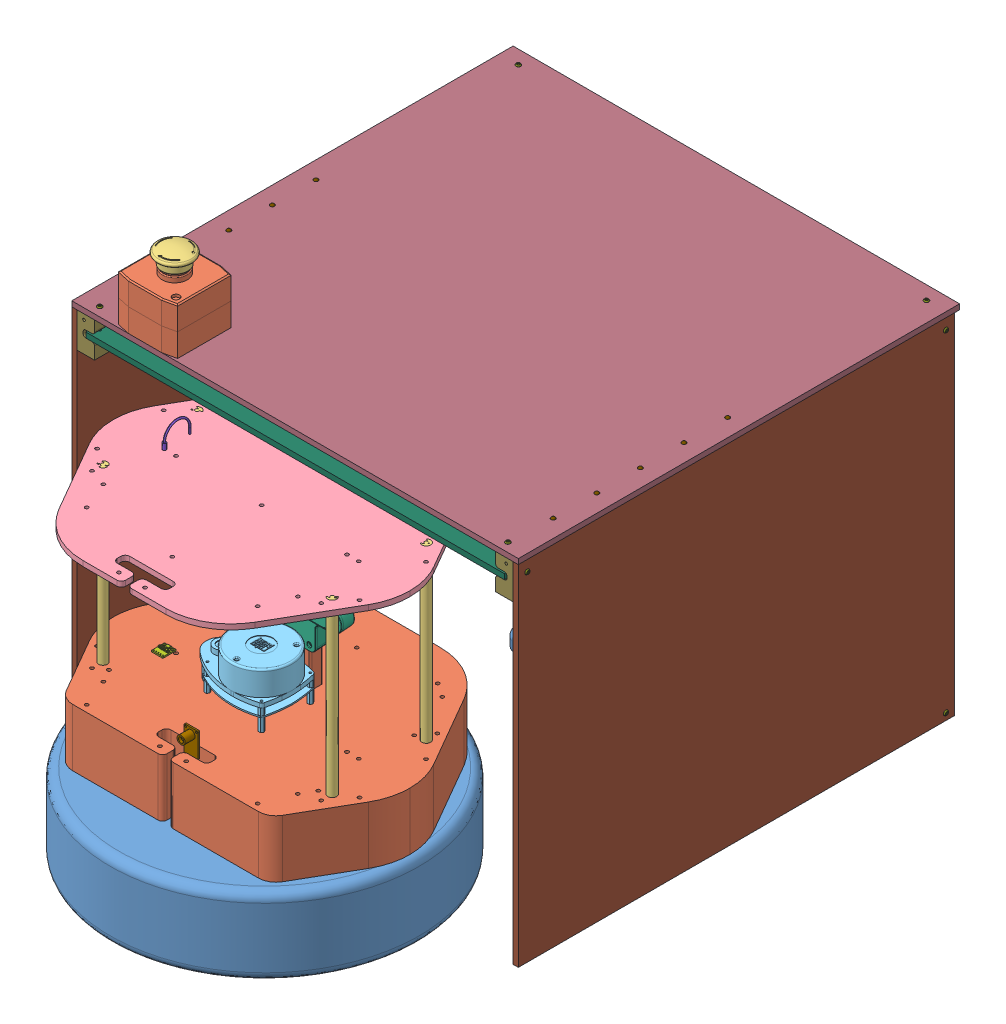
SolidWorks assembly robot_dock_with_robot, configuration Default. Lengths in mm.
Overall size (515 484.72 722.06).
59 component instances, 21 part files, 14 mates.
Components (placement in the parent):
- Turtlebot4Assem-1: Turtlebot4Assem [Default] at (298.995 1.0386 682.8626) x (-1 0 0) z (0 0 -1) size (354 373.83 354)
  - Kobuki Base-1: Kobuki Base [Default] at (151.4984 129.222 268.9926) size (354 89 354)
  - Layer A-1: Layer A [Default] at (151.4984 278.222 265.3926) size (340 111 267.27)
  - ROD-1: ROD [Default] at (282.8984 218.222 322.8926) x (-0.326124 0 0.945327) z (-0.945327 0 -0.326124) size (10 262 10)
  - ROD-2: ROD [Default] at (282.8984 218.222 215.0926) x (0.242222 0 0.970221) z (-0.970221 0 0.242222) size (10 262 10)
  - ROD-3: ROD [Default] at (20.0984 218.222 322.8926) x (0.560447 0 0.828191) z (-0.828191 0 0.560447) size (10 262 10)
  - ROD-4: ROD [Default] at (20.0984 218.222 215.0926) size (10 262 10)
  - Layer C-1: Layer C [Default] at (151.4984 474.222 265.3926) size (340 6 287.27)
  - rplidar_main-1: rplidar_main [По умолчанию] at (165.7484 308.822 265.3942) size (98.5 57.7 70.02)
  - OAK-D-parts-14sep2020.stp-3: OAK-D-parts-14sep2020.stp [Default] at (149.808 370.0152 305.3942) x (-1 0 0) z (0 0 -1) size (110 54.5 33.05)
  - OSNOVANIE.stp-1: OSNOVANIE.stp [Default] at (251.9304 284.222 252.7128) x (0.999998 0 -0.001829) z (0 1 0) size (13.1 15 3.05)
  - ds18b20.step-1: ds18b20.step [Default] at (262.9536 452.1028 265.3927) x (0.021057 0 0.999778) z (0 -1 0) size (34.1 6 75.95)
  - MLX90640-1: MLX90640 [Default] at (151.6042 285.7214 186.3926) x (-1 0 0) z (0 0 -1) size (16.02 28.28 13.12)
- robot_dock-1: robot_dock [Default] at (-102.1336 561.8362 328.3513) x (1 0 0) z (0 -1 0) size (515 507.5 407.6)
  - back_board-1: back_board [Default] at (-3.0743 -458.0455 33.4938) size (500 6 400)
  - side_board-3: side_board [Default] at (496.9257 47.9545 33.4938) x (0 -1 0) z (0 0 1) size (500 6 400)
  - side_board-4: side_board [Default] at (-9.0743 47.9545 33.4938) x (0 -1 0) z (0 0 1) size (500 6 400)
  - connector-1: connector [Default] at (-3.0743 27.9545 35.3943) size (20 20 40)
  - connector-2: connector [Default] at (496.9257 -432.0455 35.3943) x (-1 0 0) z (0 0 1) size (20 20 40)
  - connector-4: connector [Default] at (496.9257 47.9545 35.3943) x (-1 0 0) z (0 0 1) size (20 20 40)
  - connector-6: connector [Default] at (-3.0743 -452.0455 35.3943) size (20 20 40)
  - top_board-1: top_board [Default] at (-3.0743 47.9545 27.4938) x (1 0 0) z (0 -1 0) size (512 6 506)
  - back_connector-1: back_connector [Default] at (-3.0743 -452.0455 433.4938) x (1 0 0) z (0 1 0) size (20 30 20)
  - back_connector-2: back_connector [Default] at (476.9257 -452.0455 433.4938) x (1 0 0) z (0 1 0) size (20 30 20)
  - middle_board-2: middle_board [Default] at (486.9257 -452.0455 56.4938) x (0 1 0) z (-1 0 0) size (500.05 6.1 480)
  - Screw_Machine_M3x20-1: Screw_Machine_M3x20 [Default] at (488.9257 -458.0455 39.4938) x (-0.837169 0 -0.546944) z (-0.546944 0 0.837169) size (5.5 21.5 5.5)
  - Screw_Machine_M3x20-2: Screw_Machine_M3x20 [Default] at (480.9257 37.9545 27.4938) x (1 0 0) z (0 1 0) size (5.5 21.5 5.5)
  - Screw_Machine_M3x20-6: Screw_Machine_M3x20 [Default] at (4.9257 -458.0455 39.4938) x (-1 0 0) z (0 0 1) size (5.5 21.5 5.5)
  - Screw_Machine_M3x20-8: Screw_Machine_M3x20 [Default] at (502.9257 -442.0455 425.4938) x (0 0.381849 -0.924225) z (0 -0.924225 -0.381849) size (5.5 21.5 5.5)
  - Screw_Machine_M3x20-9: Screw_Machine_M3x20 [Default] at (6.9257 -458.0455 411.4938) x (-0.837169 0 -0.546944) z (-0.546944 0 0.837169) size (5.5 21.5 5.5)
  - Screw_Machine_M3x20-10: Screw_Machine_M3x20 [Default] at (-9.0743 -442.0455 45.4938) x (0 1 0) z (0 0 1) size (5.5 21.5 5.5)
  - Screw_Machine_M3x20-11: Screw_Machine_M3x20 [Default] at (-9.0743 -442.0455 425.4938) x (0 1 0) z (0 0 1) size (5.5 21.5 5.5)
  - Screw_Machine_M3x20-12: Screw_Machine_M3x20 [Default] at (-9.0743 37.9545 45.4938) x (0 1 0) z (0 0 1) size (5.5 21.5 5.5)
  - Screw_Machine_M3x20-13: Screw_Machine_M3x20 [Default] at (12.9257 -442.0455 27.4938) x (1 0 0) z (0 1 0) size (5.5 21.5 5.5)
  - Screw_Machine_M3x20-14: Screw_Machine_M3x20 [Default] at (480.9257 -442.0455 27.4938) x (1 0 0) z (0 1 0) size (5.5 21.5 5.5)
  - Screw_Machine_M3x20-16: Screw_Machine_M3x20 [Default] at (486.9257 -458.0455 411.4938) x (-0.837169 0 -0.546944) z (-0.546944 0 0.837169) size (5.5 21.5 5.5)
  - Screw_Machine_M3x20-17: Screw_Machine_M3x20 [Default] at (502.9257 -442.0455 45.4938) x (0 0.381849 -0.924225) z (0 -0.924225 -0.381849) size (5.5 21.5 5.5)
  - Screw_Machine_M3x20-19: Screw_Machine_M3x20 [Default] at (12.9257 37.9545 27.4938) x (1 0 0) z (0 1 0) size (5.5 21.5 5.5)
  - Screw_Machine_M3x20-20: Screw_Machine_M3x20 [Default] at (502.9257 37.9545 45.4938) x (0 0.381849 -0.924225) z (0 -0.924225 -0.381849) size (5.5 21.5 5.5)
  - robot_dock_pilot-1: robot_dock_pilot [Default] at (151.9257 -452.0455 433.4938) x (1 0 0) z (0 1 0) size (20 30 20)
  - robot_dock_pilot-2: robot_dock_pilot [Default] at (321.9257 -452.0455 433.4938) x (1 0 0) z (0 1 0) size (20 30 20)
  - Led Lamp 5 mm 3-1: Led Lamp 5 mm 3 [Default] at (482.9257 -12.0455 34.4938) x (0 0 -1) z (1 0 0) size (35.6 5.45 5.9)
  - Led Lamp 5 mm 3-2: Led Lamp 5 mm 3 [Default] at (10.9257 -212.0455 34.4938) x (0 0 -1) z (1 0 0) size (35.6 5.45 5.9)
  - Led Lamp 5 mm 3-3: Led Lamp 5 mm 3 [Default] at (10.9257 -62.0455 34.4938) x (0 0 -1) z (1 0 0) size (35.6 5.45 5.9)
  - Led Lamp 5 mm 3-4: Led Lamp 5 mm 3 [Default] at (10.9257 -12.0455 34.4938) x (0 0 -1) z (1 0 0) size (35.6 5.45 5.9)
  - Led Lamp 5 mm 3-5: Led Lamp 5 mm 3 [Default] at (482.9257 -212.0455 34.4938) x (0 0 -1) z (1 0 0) size (35.6 5.45 5.9)
  - Led Lamp 5 mm 3-6: Led Lamp 5 mm 3 [Default] at (482.9257 -162.0455 34.4938) x (0 0 -1) z (1 0 0) size (35.6 5.45 5.9)
  - Led Lamp 5 mm 3-7: Led Lamp 5 mm 3 [Default] at (10.9257 -162.0455 34.4938) x (0 0 -1) z (1 0 0) size (35.6 5.45 5.9)
  - Led Lamp 5 mm 3-8: Led Lamp 5 mm 3 [Default] at (10.9257 -112.0455 34.4938) x (0 0 -1) z (1 0 0) size (35.6 5.45 5.9)
  - Led Lamp 5 mm 3-10: Led Lamp 5 mm 3 [Default] at (482.9257 -112.0455 34.4938) x (0 0 -1) z (1 0 0) size (35.6 5.45 5.9)
  - Led Lamp 5 mm 3-11: Led Lamp 5 mm 3 [Default] at (482.9257 -62.0455 34.4938) x (0 0 -1) z (0.182556 -0.983195 0) size (35.6 5.45 5.9)
- Dock-1: Dock [Default] at (69.7921 128.3424 -123.6942) x (0 0 1) z (-1 0 0) size (200.3 135.31 152.91)
- Screw_Machine_M3x20-1: Screw_Machine_M3x20 [Default] at (59.7921 136.3424 -129.6942) x (-0.923728 -0.383049 0) z (0.383049 -0.923728 0) size (5.5 21.5 5.5)
- Screw_Machine_M3x20-2: Screw_Machine_M3x20 [Default] at (229.7921 150.3424 -129.6942) x (-0.923728 -0.383049 0) z (0.383049 -0.923728 0) size (5.5 21.5 5.5)
- Screw_Machine_M3x20-3: Screw_Machine_M3x20 [Default] at (229.7921 136.3424 -129.6942) x (-0.923728 -0.383049 0) z (0.383049 -0.923728 0) size (5.5 21.5 5.5)
- Screw_Machine_M3x20-4: Screw_Machine_M3x20 [Default] at (59.7921 150.3424 -129.6942) x (-0.923728 -0.383049 0) z (0.383049 -0.923728 0) size (5.5 21.5 5.5)
- E-Stop-1: E-Stop [Engaged] at (-90.6583 580.3163 385.8938) x (1 0 0) z (0 1 0) size (68 68 78.72)
  - E-Stop-2: E-Stop [Default] at (63.4505 9.588 -45.9739) size (68 68 73.5)
  - E-Stop Red Mushroom-1: E-Stop Red Mushroom [Default] at (63.4505 9.588 -58.2553) size (40 40 17.5)
Mates (geometry in assembly coordinates):
- Coincident1: coincident aligned: line of robot_dock-1/robot_dock_pilot-1 through (69.7921 158.3424 -123.6942) axis (0 -1 0); line of Dock-1 through (69.7921 248.3424 -123.6942) axis (0 -1 0)
- Coincident2: coincident aligned: line of robot_dock-1/robot_dock_pilot-2 through (219.7921 158.3424 -123.6942) axis (0 -1 0); line of Dock-1 through (219.7921 248.3424 -123.6942) axis (0 -1 0)
- Coincident3: coincident anti-aligned: line of robot_dock-1/robot_dock_pilot-1 through (69.7921 128.3424 -103.6942) axis (0 0 -1); line of Dock-1 through (69.7921 128.3424 -123.6942) axis (0 0 1)
- Concentric1: concentric aligned: cylinder of robot_dock-1/back_board-1 through (229.7921 136.3424 -133.6942) axis (0 0 1) radius 1.5; cylinder of Screw_Machine_M3x20-3 through (229.7921 136.3424 -109.6942) axis (0 0 1) radius 1.5
- Concentric2: concentric aligned: cylinder of robot_dock-1/back_board-1 through (229.7921 150.3424 -133.6942) axis (0 0 1) radius 1.5; cylinder of Screw_Machine_M3x20-2 through (229.7921 150.3424 -109.6942) axis (0 0 1) radius 1.5
- Concentric3: concentric aligned: cylinder of robot_dock-1/back_board-1 through (59.7921 150.3424 -133.6942) axis (0 0 1) radius 1.5; cylinder of Screw_Machine_M3x20-4 through (59.7921 150.3424 -109.6942) axis (0 0 1) radius 1.5
- Concentric4: concentric aligned: cylinder of robot_dock-1/back_board-1 through (59.7921 136.3424 -133.6942) axis (0 0 1) radius 1.5; cylinder of Screw_Machine_M3x20-1 through (59.7921 136.3424 -109.6942) axis (0 0 1) radius 1.5
- Coincident4: coincident anti-aligned: plane of robot_dock-1/back_board-1 through (-105.2079 528.3424 -129.6942) normal (0 0 -1); circle of Screw_Machine_M3x20-4
- Coincident5: coincident anti-aligned: plane of robot_dock-1/back_board-1 through (-105.2079 528.3424 -129.6942) normal (0 0 -1); plane of Screw_Machine_M3x20-1 through (60.7902 133.9355 -129.6942) normal (0 0 1)
- Coincident6: coincident anti-aligned: plane of robot_dock-1/back_board-1 through (-105.2079 528.3424 -129.6942) normal (0 0 -1); circle of Screw_Machine_M3x20-3
- Coincident7: coincident anti-aligned: plane of robot_dock-1/back_board-1 through (-105.2079 528.3424 -129.6942) normal (0 0 -1); plane of Screw_Machine_M3x20-2 through (230.7902 147.9355 -129.6942) normal (0 0 1)
- Coincident8: coincident anti-aligned: plane of robot_dock-1/top_board-1 through (-105.2079 534.3424 376.3058) normal (0 1 0); plane of E-Stop-1/E-Stop-2 through (-27.2079 534.3424 376.3058) normal (0 -1 0)
- Coincident9: coincident aligned: line of robot_dock-1/top_board-1 through (400.7921 534.3424 376.3058) axis (-1 0 0); line of E-Stop-1/E-Stop-2 through (-8.2079 534.3424 376.3058) axis (-1 0 0)
- Distance2: distance = 50 mm: line of E-Stop-1/E-Stop-2 through (-61.2079 534.3424 372.9804) axis (0 0 -1); line of robot_dock-1/top_board-1 through (-111.2079 534.3424 -129.6942) axis (0 0 1)
